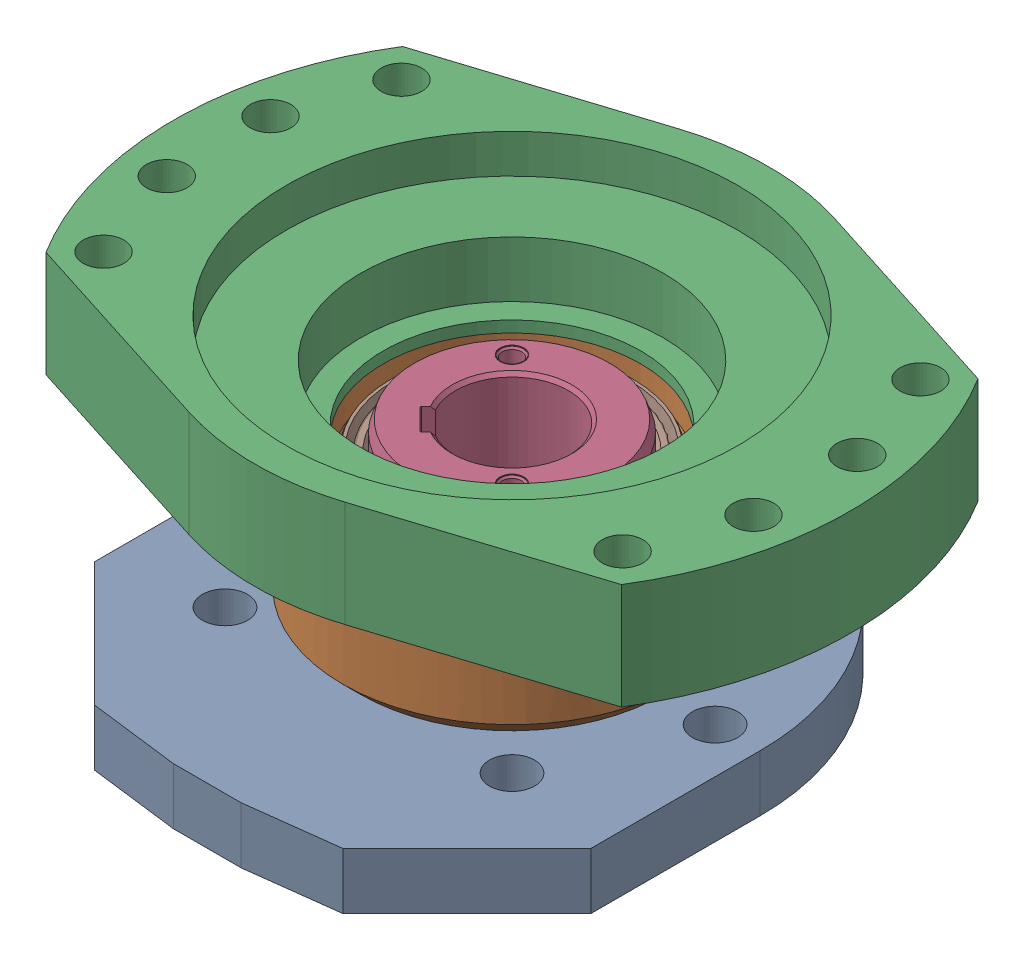
SolidWorks assembly g1_3_1_1_1_3, configuration 默认. Lengths in mm.
Overall size (300 165.8 249).
13 component instances, 8 part files, 0 mates.
Components (placement in the parent):
- g1_3_1_1_1_1_2-1: g1_3_1_1_1_1_2 [默认] at origin size (300 154 249)
  - g1_3_1_1_1_1-1_af0_2-1: g1_3_1_1_1_1-1_af0_2 [默认] at origin size (220 42 245)
  - g1_3_1_1_1_1-2_af0_2-1: g1_3_1_1_1_1-2_af0_2 [默认] at (0 50 0) size (150 65.01 150)
  - g1_3_1_1_1_1-3_af0_2-1: g1_3_1_1_1_1-3_af0_2 [默认] at (0 140 0) size (300 47 228)
- g1_3_1_1_1-2_2-1: g1_3_1_1_1-2_2 [默认] at (0 122.2 0) x (0.707107 0 0.707107) z (0.707107 0 -0.707107) size (90 126 90)
- g1_3_1_1_1-1_2-1: g1_3_1_1_1-1_2 [默认] at (0 77 0) x (0 1 0) z (0 0 1) size (20 110 110)
- b90x110x12_gb9877_1_2-1: b90x110x12_gb9877_1_2 [默认] at (0 66.9 0) size (108.6 17.9 108.6)
  - b90x110x12_gb9877_1_rubber_2-1: b90x110x12_gb9877_1_rubber_2 [默认] at origin size (108.6 12 108.6)
  - b90x110x12_gb9877_1_frame_2-1: b90x110x12_gb9877_1_frame_2 [默认] at (0 -2.4 0) x (-1 0 0) z (0 0 1) size (107.2 9.5 107.2)
- b90x110x12_gb9877_1_2-2: b90x110x12_gb9877_1_2 [默认] at (0 104.8 0) size (108.6 17.9 108.6)
  - b90x110x12_gb9877_1_rubber_2-1: b90x110x12_gb9877_1_rubber_2 [默认] at origin size (108.6 12 108.6)
  - b90x110x12_gb9877_1_frame_2-1: b90x110x12_gb9877_1_frame_2 [默认] at (0 -2.4 0) x (-1 0 0) z (0 0 1) size (107.2 9.5 107.2)
- 80_gb894_1_2-1: 80_gb894_1_2 [默认] at (-2.4 11.1 -38.1746) x (1 0 0) z (0 -1 0) size (85.83 90.87 2.5)
